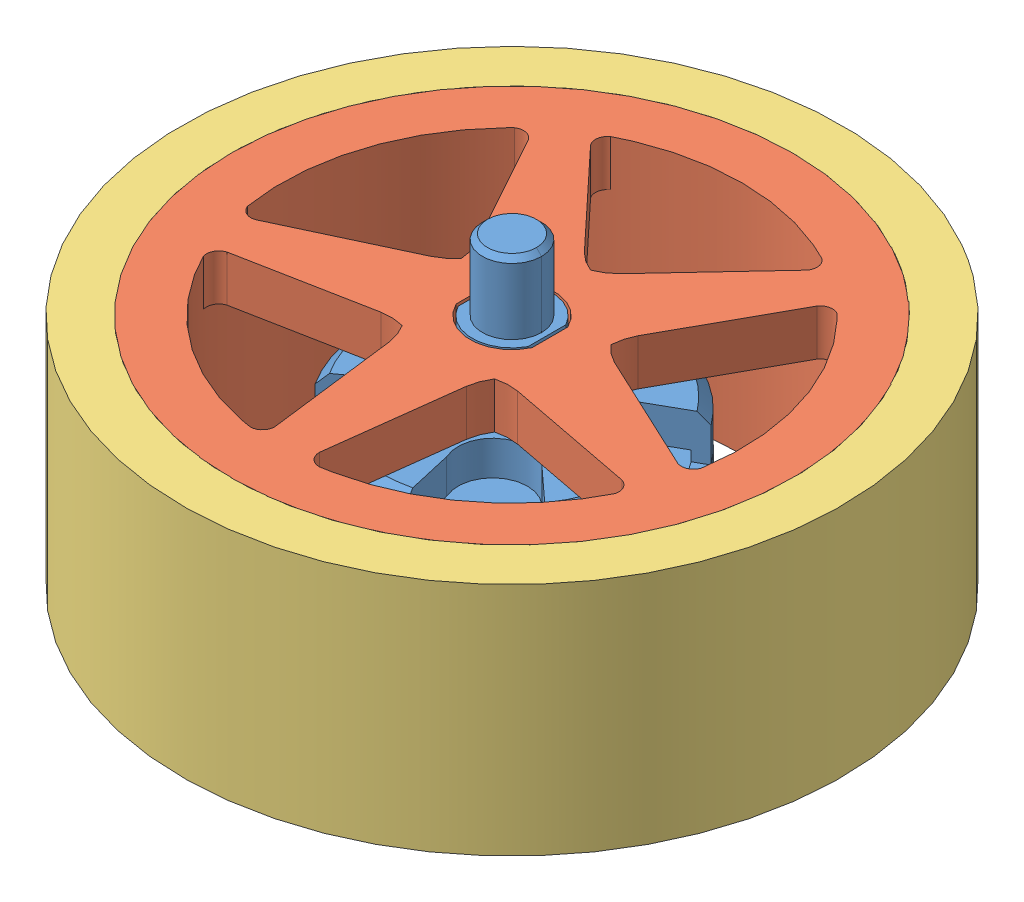
SolidWorks assembly testbed, configuration Default. Lengths in mm.
Overall size (89.28 39.36 89.28).
3 component instances, 3 part files, 4 mates.
Components (placement in the parent):
- motor_2212-920kv-2: motor_2212-920kv [Default] at (11.4606 2.2663 32.312) size (27.92 39.36 27.92)
- wheel-2: wheel [Default] at (11.4606 28.4063 32.312) x (-1 0 0) z (0 0 -1) size (55 23 55)
- tire-1: tire [Default] at (11.4606 9.9063 32.312) x (0 1 0) z (-0.546944 0 0.837169) size (23 64.5 64.5)
Mates (geometry in assembly coordinates):
- Concentric1: concentric aligned: circle of motor_2212-920kv-2; circle of wheel-2
- Coincident2: coincident aligned: plane of motor_2212-920kv-2 through (11.4606 32.9063 32.312) normal (0 1 0); plane of wheel-2 through (11.4606 32.9063 32.312) normal (0 1 0)
- Parallel2: parallel aligned: line of motor_2212-920kv-2 through (14.8801 32.9063 34.1665) axis (0 0 -1); line of wheel-2 through (15.1683 32.9063 34.062) axis (0 0 -1)
- Coincident4: coincident aligned: circle of wheel-2; circle of tire-1
